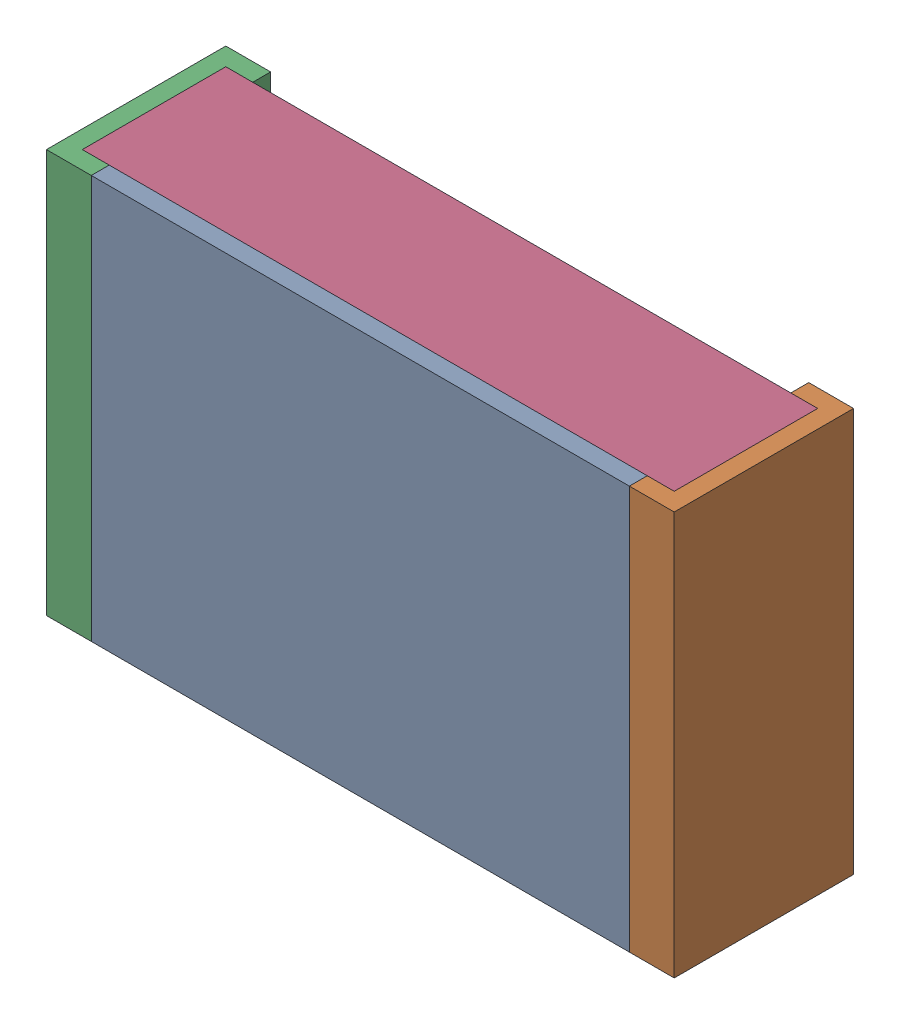
SolidWorks assembly RESC2012X06N.step-1, configuration По умолчанию. Lengths in mm.
Overall size (2.1 1.35 0.6).
4 component instances, 3 part files, 0 mates.
Components (placement in the parent):
- RESC2012X06N.step-Part-1-1: RESC2012X06N.step-Part-1 [По умолчанию] at (-0.9 -0.675 0.54) size (1.8 1.35 0.06)
- RESC2012X06N.step-Part-2-1: RESC2012X06N.step-Part-2 [По умолчанию] at (1.05 0.675 0) x (-1 0 0) z (0 0 1) size (0.15 1.35 0.6)
- RESC2012X06N.step-Part-2-2: RESC2012X06N.step-Part-2 [По умолчанию] at (-1.05 -0.675 0) size (0.15 1.35 0.6)
- RESC2012X06N.step-Part-3-1: RESC2012X06N.step-Part-3 [По умолчанию] at (-1.05 -0.675 0) size (1.98 1.35 0.48)
